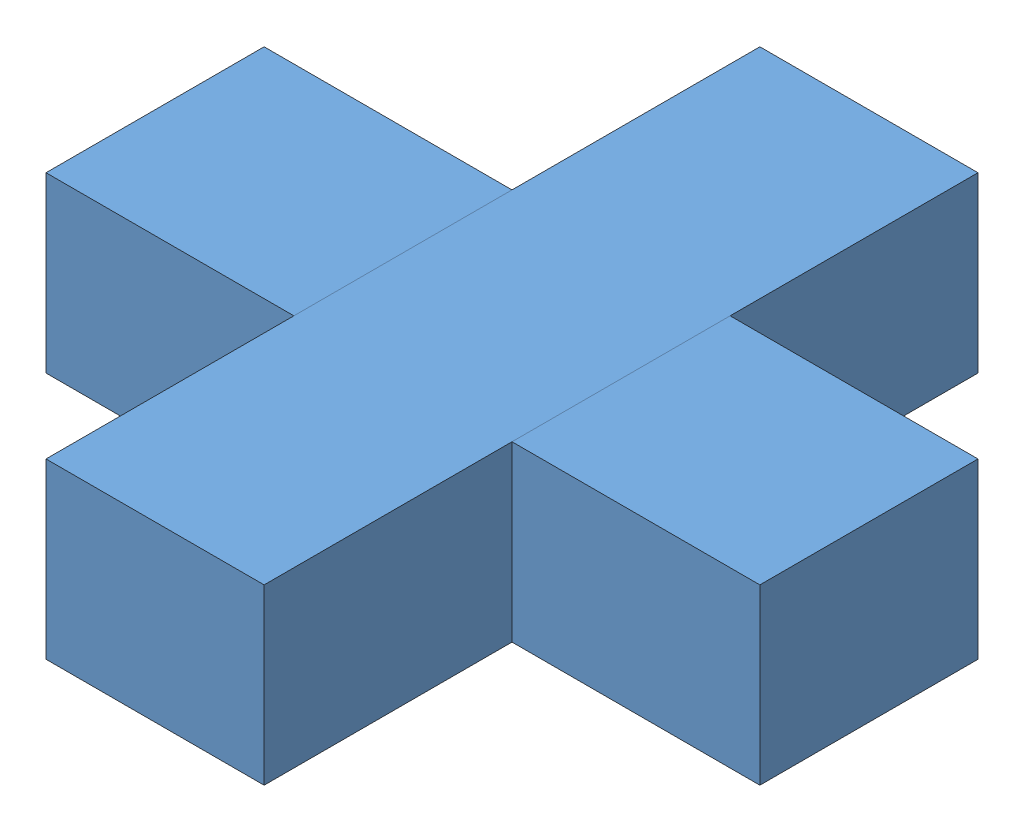
SolidWorks assembly CROSS H Exploded ASS, configuration Default. Lengths in mm.
Overall size (144 141.85 144).
2 component instances, 1 part files, 3 mates.
Components (placement in the parent):
- CROSS HALVING-1: CROSS HALVING [Default] at (-122.4608 41.0705 -22) size (144 35 44)
- CROSS HALVING-2: CROSS HALVING [Default] at (-28.4608 76.0705 72) x (0 0 -1) z (-1 0 0) size (144 35 44)
Mates (geometry in assembly coordinates):
- Coincident11: coincident anti-aligned: plane of CROSS HALVING-1 through (-72.4608 58.5705 22) normal (0 1 0)
- Coincident12: coincident anti-aligned: line of CROSS HALVING-1 through (-28.4608 58.5705 22) axis (-1 0 0); line of CROSS HALVING-2 through (-72.4608 58.5705 22) axis (1 0 0)
- Coincident13: coincident anti-aligned: line of CROSS HALVING-1 through (-28.4608 58.5705 22) axis (0 0 -1); line of CROSS HALVING-2 through (-28.4608 58.5705 -22) axis (0 0 1)
